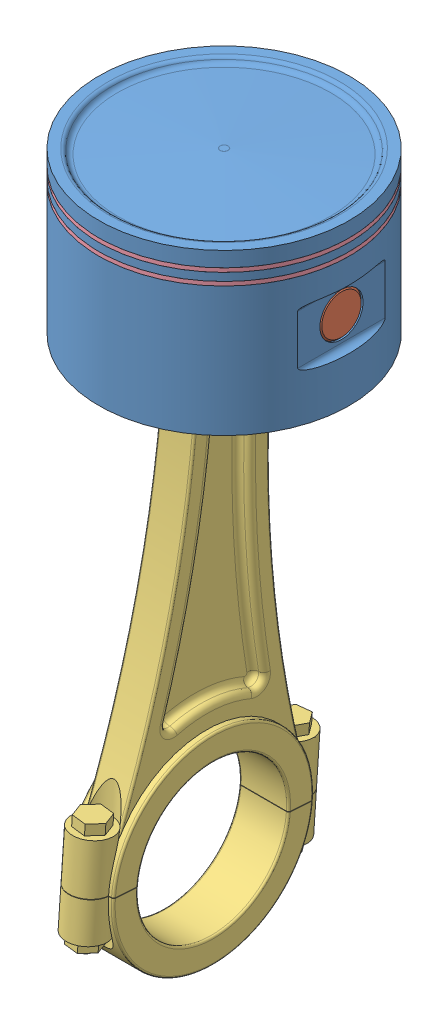
SolidWorks assembly 04. Piston Assembly, configuration Default. Lengths in mm.
Overall size (127.04 347.66 145.68).
5 component instances, 4 part files, 8 mates.
Components (placement in the parent):
- 04. Piston Head-1: 04. Piston Head [Default] at (63.9037 47.5378 101.5605) size (127.04 81.28 127)
- 04. Connecting Pin-1: 04. Connecting Pin [Default] at (63.9037 85.5378 101.5605) size (119 22 22)
- 04. Connecting Rod-1: 04. Connecting Rod [Default] at (63.9037 -39.1414 110.5105) x (0 0.0716 0.997433) z (-1 0 0) size (121.6 321.8 32)
- 04. Piston Ring-1: 04. Piston Ring [Default] at (63.9037 114.1978 101.5605) size (127 2 127)
- 04. Piston Ring-2: 04. Piston Ring [Default] at (63.9037 120.1978 101.5605) size (127 2 127)
Mates (geometry in assembly coordinates):
- Concentric1: concentric aligned: cylinder of 04. Piston Ring-1 through (63.9037 115.1978 101.5605) axis (0 -1 0) radius 63.5; cylinder of 04. Piston Ring-2 through (63.9037 121.1978 101.5605) axis (0 -1 0) radius 63.5
- Coincident1: coincident anti-aligned: plane of 04. Piston Head-1 through (127.4037 121.1978 101.5605) normal (0 -1 0); plane of 04. Piston Ring-2 through (63.9037 121.1978 101.5605) normal (0 1 0)
- Coincident2: coincident anti-aligned: plane of 04. Piston Head-1 through (127.4037 115.1978 101.5605) normal (0 -1 0); plane of 04. Piston Ring-1 through (63.9037 115.1978 101.5605) normal (0 1 0)
- Concentric2: concentric aligned: cylinder of 04. Piston Head-1 through (63.9037 47.5378 101.5605) axis (0 -1 0) radius 63.5; cylinder of 04. Piston Ring-1 through (63.9037 115.1978 101.5605) axis (0 -1 0) radius 63.5
- Concentric3: concentric anti-aligned: cylinder of 04. Connecting Pin-1 through (123.4037 85.5378 101.5605) axis (-1 0 0) radius 11; cylinder of 04. Connecting Rod-1 through (47.9037 85.5378 101.5605) axis (1 0 0) radius 11
- Width1: width anti-aligned: plane of 04. Connecting Rod-1 through (79.9037 -39.1414 110.5105) normal (1 0 0); plane of 04. Connecting Rod-1 through (47.9037 -39.1414 110.5105) normal (-1 0 0); plane of 04. Connecting Pin-1 through (4.4037 85.5378 101.5605) normal (-1 0 0); plane of 04. Connecting Pin-1 through (123.4037 85.5378 101.5605) normal (1 0 0)
- Width2: width anti-aligned: plane of 04. Piston Head-1 through (123.4037 70.5378 38.0605) normal (1 0 0); plane of 04. Piston Head-1 through (4.4037 70.5378 38.0605) normal (-1 0 0); plane of 04. Connecting Pin-1 through (4.4037 85.5378 101.5605) normal (-1 0 0); plane of 04. Connecting Pin-1 through (123.4037 85.5378 101.5605) normal (1 0 0)
- Concentric4: concentric anti-aligned: cylinder of 04. Piston Head-1 through (0.3837 85.5378 101.5605) axis (1 0 0) radius 11; cylinder of 04. Connecting Pin-1 through (123.4037 85.5378 101.5605) axis (-1 0 0) radius 11
